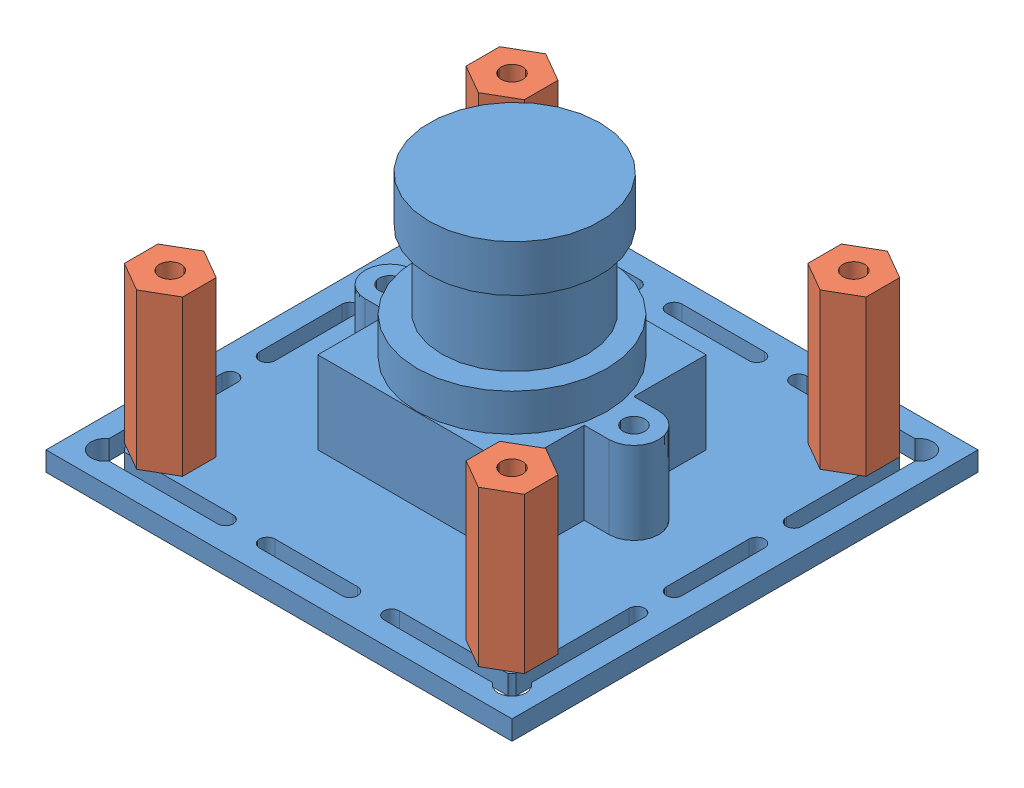
SolidWorks assembly camera_assembly, configuration Default. Lengths in mm.
Overall size (38.1 29.53 38.1).
5 component instances, 2 part files, 3 mates.
Components (placement in the parent):
- ELP_cam-1: ELP_cam [Default] at origin size (38.1 29.53 38.1)
- standoff-1: standoff [Default] at (-238.6218 1.5875 329.6432) x (0.952522 0 0.304471) z (-0.304471 0 0.952522) size (5.37 12.7 5.24)
- standoff-2: standoff [Default] at (-266.5618 1.5875 329.6432) x (0.952522 0 0.304471) z (-0.304471 0 0.952522) size (5.37 12.7 5.24)
- standoff-3: standoff [Default] at (-238.6218 1.5875 301.7032) x (0.952522 0 0.304471) z (-0.304471 0 0.952522) size (5.37 12.7 5.24)
- standoff-4: standoff [Default] at (-266.5618 1.5875 301.7032) x (0.952522 0 0.304471) z (-0.304471 0 0.952522) size (5.37 12.7 5.24)
Mates (geometry in assembly coordinates):
- Concentric1: concentric aligned: circle of ELP_cam-1; circle of standoff-1
- Parallel1: parallel aligned: plane of ELP_cam-1 through (-233.5418 1.5875 296.6232) normal (1 0 0); plane of standoff-1 through (-236.2405 14.2875 331.018) normal (1 0 0)
- Coincident3: coincident anti-aligned: plane of ELP_cam-1 through (0 1.5875 0) normal (0 1 0); plane of standoff-1 through (-238.6218 1.5875 329.6432) normal (0 -1 0)
